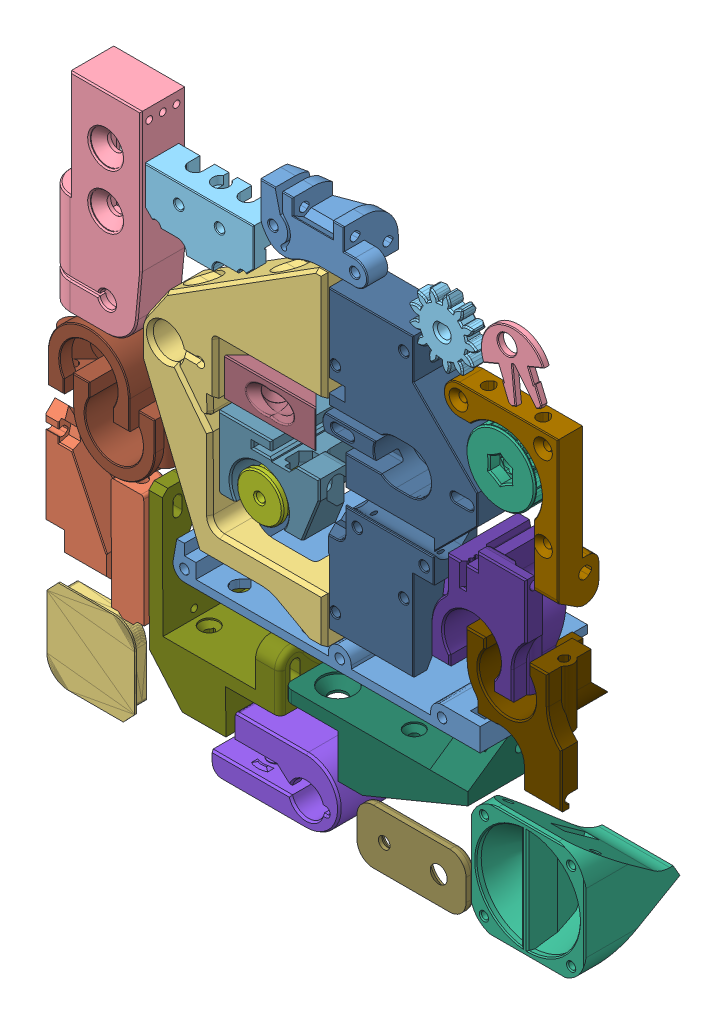
SolidWorks assembly PrintTray, configuration Default. Lengths in mm.
Overall size (200 201.83 80.1).
25 component instances, 24 part files, 41 mates.
Components (placement in the parent):
- 407-1: 407 [Default] at (-15.0826 86.581 -20) size (39.3 20.5 20)
- 425-1: 425 [Default] at (-98.622 -33.5926 -4.2999) x (0 -0.707107 -0.707107) z (1 0 0) size (41.5 33.5 22.5)
- 437-1: 437 [Default] at (-54.4911 29.6968 -14) size (67.1 119 22)
- 438-1: 438 [Default] at (-75.982 32.4554 0) x (0 -1 0) z (0 0 -1) size (77 35 16)
- 440-1: 440 [Default] at (47.0179 83.7042 -5) size (24.94 25.13 8)
- 441-1: 441 [Default] at (68.2774 50.6103 -10) size (25.3 25.3 13)
- 442-1: 442 [Default] at (-20.0083 -2.5369 0) x (0 0 1) z (-1 0 0) size (53 17 17)
- 462-1: 462 [Default] at (-2.8694 -90.0511 0) x (1 0 0) z (0 0 -1) size (47 24 20)
- 469-1: 469 [Default] at (68.5039 49.719 -9) size (42 57.25 15.29)
- 473-1: 473 [Default] at (29.8778 33.607 0) x (-1 0 0) z (0 0 -1) size (60.5 108.5 22)
- 492-1: 492 [Default] at (-82.8022 5.0588 0) x (-1 0 0) z (0 0 -1) size (33.1 25.5 30)
- 492-2: 492 [Default] at (-73.48 -7.5246 0) x (1 0 0) z (0 0 -1) size (33.1 25.5 30)
- 503-1: 503 [Default] at (45.7554 -89.1386 0) x (-1 0 0) z (0 0 -1) size (40 20 3.7)
- 527-1: 527 [Default] at (0.7904 22.4468 0) x (-1 0 0) z (0 0 -1) size (33.46 14 17)
- 546-1: 546 [Default] at (-20.0997 -2.1484 -23) x (1 0 0) z (0 1 0) size (38 60 36)
- 547-1: 547 [Default] at (-1.226 -62.0512 -20) x (1 0 0) z (0 1 0) size (67.7 40 32.1)
- 548-1: 548 [Default] at (-22.4307 -68.5441 -22) x (-0.999991 -0.004271 0) z (-0.004271 0.999991 0) size (48 42 66.5)
- 549-1: 549 [Default] at (57.7793 -10.7376 0) x (-1 0 0) z (0 0 -1) size (36.4 41.5 26)
- 550-1: 550 [Default] at (70.6951 -16.1197 0) x (1 0 0) z (0 0 -1) size (36.4 41.5 37)
- 820-1: 820 [Default] at (9.4566 -38.8135 -57.5) size (112.7 12.4 57.5)
- 821-1: 821 [Default] at (-74.4913 -23.163 0) x (0.004271 -0.999991 0) z (0.999991 0.004271 0) size (42.7 11.15 12)
- logo-1: logo [Default] at (-98.0431 -98.6302 0) x (0 1 0) z (0 0 -1) size (32.31 32.25 5.6)
- 525-1: 525 [Default] at (75.4138 80.6105 0) x (-0.923728 -0.383049 0) z (0 0 -1) size (24 24 2.1)
- 1079-1: 1079 [Default] at (-42.1713 60.9074 0) x (-1 0 0) z (0 0 -1) size (40 22 12.5)
- 1123-1: 1123 [Default] at (57.3382 -99.1297 -2) x (0 0.5 -0.866025) z (1 0 0) size (39.54 37.17 44.25)
Mates (geometry in assembly coordinates):
- Coincident1: coincident aligned: plane of 407-1 through (14.9174 86.581 0) normal (0 0 1); plane of assembly through (0 0 0) normal (0 0 1)
- Coincident2: coincident aligned: plane of 425-1 through (-76.122 -21.9613 0) normal (0 0 1); plane of assembly through (0 0 0) normal (0 0 1)
- Coincident3: coincident aligned: plane of 437-1 through (-40.3907 15.3863 0) normal (0 0 1); plane of assembly through (0 0 0) normal (0 0 1)
- Coincident4: coincident aligned: plane of 438-1 through (-75.982 32.4554 0) normal (0 0 1); plane of assembly through (0 0 0) normal (0 0 1)
- Coincident5: coincident aligned: plane of 440-1 through (47.0179 83.7042 0) normal (0 0 1); plane of assembly through (0 0 0) normal (0 0 1)
- Coincident6: coincident aligned: plane of 441-1 through (68.2774 50.6103 0) normal (0 0 1); plane of assembly through (0 0 0) normal (0 0 1)
- Coincident7: coincident aligned: plane of 442-1 through (-11.5083 -2.5369 0) normal (0 0 1); plane of assembly through (0 0 0) normal (0 0 1)
- Coincident8: coincident aligned: plane of 462-1 through (-2.8694 -87.0511 0) normal (0 0 1); plane of assembly through (0 0 0) normal (0 0 1)
- Coincident9: coincident aligned: plane of 469-1 through (68.5039 49.719 0) normal (0 0 1); plane of assembly through (0 0 0) normal (0 0 1)
- Coincident10: coincident aligned: plane of 473-1 through (7.9575 33.607 0) normal (0 0 1); plane of assembly through (0 0 0) normal (0 0 1)
- Coincident11: coincident aligned: plane of 492-1 through (-82.8022 5.0588 0) normal (0 0 1); plane of assembly through (0 0 0) normal (0 0 1)
- Coincident12: coincident aligned: plane of 492-2 through (-73.48 -7.5246 0) normal (0 0 1); plane of assembly through (0 0 0) normal (0 0 1)
- Coincident13: coincident aligned: plane of ? through (165.8154 163.1763 0) normal (0 0 1); plane of assembly through (0 0 0) normal (0 0 1)
- Coincident14: coincident aligned: plane of 503-1 through (45.7554 -89.1386 0) normal (0 0 1); plane of assembly through (0 0 0) normal (0 0 1)
- Coincident15: coincident aligned: plane of 527-1 through (0.7904 36.4468 0) normal (0 0 1); plane of assembly through (0 0 0) normal (0 0 1)
- Coincident16: coincident aligned: plane of 546-1 through (-20.0997 -2.1484 0) normal (0 0 1); plane of assembly through (0 0 0) normal (0 0 1)
- Coincident17: coincident aligned: plane of 547-1 through (56.474 -57.5512 0) normal (0 0 1); plane of assembly through (0 0 0) normal (0 0 1)
- Coincident18: coincident aligned: plane of 548-1 through (-60.4496 -64.2064 0) normal (0 0 1); plane of assembly through (0 0 0) normal (0 0 1)
- Coincident19: coincident aligned: plane of 549-1 through (57.7793 -10.7376 0) normal (0 0 1); plane of assembly through (0 0 0) normal (0 0 1)
- Coincident20: coincident aligned: plane of 550-1 through (70.6951 -16.1197 0) normal (0 0 1); plane of assembly through (0 0 0) normal (0 0 1)
- Coincident21: coincident aligned: plane of 820-1 through (-47.5434 -38.8135 0) normal (0 0 1); plane of assembly through (0 0 0) normal (0 0 1)
- Coincident22: coincident aligned: plane of 821-1 through (-62.4914 -23.1118 0) normal (0 0 1); plane of assembly through (0 0 0) normal (0 0 1)
- Parallel1: parallel anti-aligned: line of 473-1 through (59.8778 38.9624 -16) axis (0 -1 0); line of assembly
- Parallel2: parallel aligned: line of 437-1 through (3.5089 40.1968 -14) axis (0 1 0); line of assembly
- Parallel4: parallel anti-aligned: plane of 473-1 through (36.3778 -31.393 -16) normal (1 0 0); plane of 549-1 through (65.7724 0.2624 -11.4) normal (-1 0 0)
- Parallel5: parallel anti-aligned: plane of 473-1 through (36.3778 -31.393 -16) normal (1 0 0); plane of 550-1 through (55.6951 -5.6197 -26) normal (-1 0 0)
- Parallel7: parallel anti-aligned: plane of 437-1 through (-38.4911 -21.8032 0) normal (0.999991 0.004271 0); plane of 548-1 through (-60.4496 -64.2064 0) normal (-0.999991 -0.004271 0)
- Parallel8: parallel aligned: plane of 548-1 through (-60.4496 -64.2064 0) normal (-0.999991 -0.004271 0); plane of 821-1 through (-74.4913 -23.163 0) normal (-0.999991 -0.004271 0)
- Parallel9: parallel aligned: plane of 437-1 through (3.5089 40.1968 0) normal (0 -1 0); plane of 527-1 through (0.7904 22.4468 0) normal (0 -1 0)
- Parallel10: parallel anti-aligned: plane of 492-1 through (-91.8022 -5.4412 0) normal (1 0 0); plane of 492-2 through (-88.48 -7.5246 -30) normal (-1 0 0)
- Parallel11: parallel aligned: plane of 473-1 through (36.3778 77.107 -16) normal (1 0 0); plane of 492-2 through (-58.48 2.9754 -30) normal (1 0 0)
- Parallel17: parallel: plane of 438-1 through (-75.982 21.4554 -16) normal (0 -1 0); line of assembly
- Parallel18: parallel: plane of 425-1 through (-98.622 -18.6373 -1.3654) normal (-1 0 0); line of assembly
- Parallel20: parallel anti-aligned: plane of 462-1 through (-2.8694 -75.0511 -20) normal (0 1 0); plane of 547-1 through (-8.226 -62.0512 -3) normal (0 -1 0)
- Parallel21: parallel aligned: plane of 503-1 through (15.7554 -99.1386 -3.7) normal (0 -1 0); plane of 547-1 through (-8.226 -62.0512 -3) normal (0 -1 0)
- Coincident23: coincident aligned: plane of logo-1 through (-98.0431 -98.6302 0) normal (0 0 1); plane of assembly through (0 0 0) normal (0 0 1)
- Parallel22: parallel aligned: plane of 462-1 through (-2.8694 -99.0511 -20) normal (0 -1 0); plane of logo-1 through (-98.0431 -97.3162 0) normal (0 -1 0)
- Coincident24: coincident aligned: plane of 549-1 through (57.7793 -10.7376 0) normal (0 0 1); plane of 525-1 through (73.1155 86.1529 0) normal (0 0 1)
- Coincident25: coincident aligned: plane of 437-1 through (-40.3907 15.3863 0) normal (0 0 1); plane of 1079-1 through (-22.1713 82.9074 0) normal (0 0 1)
- Coincident27: coincident aligned: plane of 1123-1 through (99.3382 -99.1297 0) normal (0 0 1); plane of assembly through (0 0 0) normal (0 0 1)
- Parallel23: parallel: plane of 1123-1 through (57.3382 -99.1297 -2) normal (-1 0 0); line of assembly
